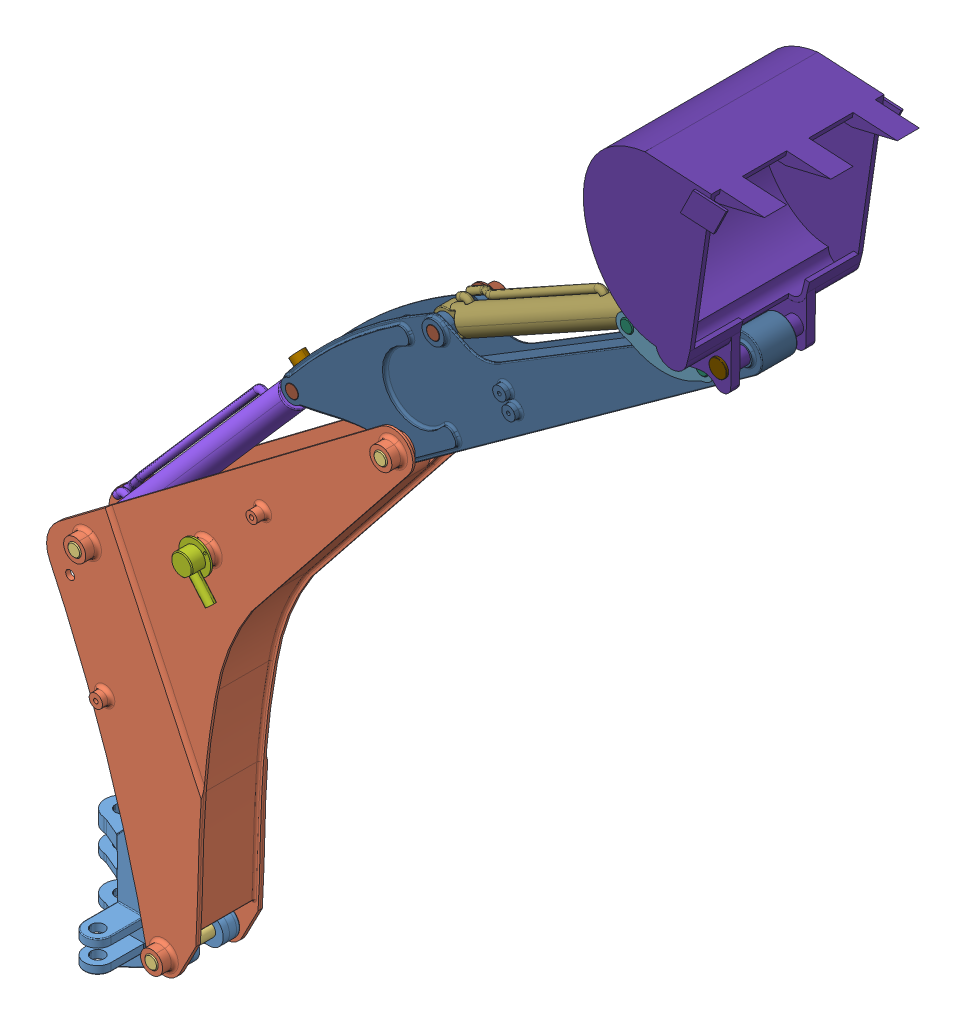
SolidWorks assembly full_assembly, configuration Default. Lengths in mm.
Overall size (1952.98 2370.5 400).
24 component instances, 18 part files, 57 mates.
Components (placement in the parent):
- kingpost-1: kingpost [Default] at origin size (240 290 226)
- boom-4: boom [Default] at (-88.6073 555.0305 -13.75) x (-0.907483 0.420088 0) z (0 0 1) size (576.32 1423.86 198.4)
- boom_pins-1: boom_pins [Default] at (85 -164.3168 63.95) x (-0.343419 0.939182 0) z (0 0 1) size (30 30 195)
- boom_cylinder_barrel-1: boom_cylinder_barrel [Default] at (165.9914 623.896 56.5) x (-0.257112 -0.966382 0) z (-0.966382 0.257112 0) size (614 75.5 93)
- boom_cylinder_rod-1: boom_cylinder_rod [Default] at (155.7069 585.2407 56.5) x (-0.257112 -0.966382 0) z (0.966382 -0.257112 0) size (638.1 60 65)
- kingpost_pin-1: kingpost_pin [Default] at (0 0 56) x (0.057056 0.998371 0) z (0 0 1) size (30 30 118)
- lp1_modification01-1: lp1_modification01 [Default] at (178.847 672.2151 151.75) x (0 0 -1) z (0.761257 0.64845 0) size (210.51 115 72)
- stick_cylinder_barrel-2: stick_cylinder_barrel [Default] at (-64.3049 582.9302 56.5) x (0.656822 0.754046 0) z (-0.754046 0.656822 0) size (632 60 78.05)
- stick_cylinder_rod-1: stick_cylinder_rod [Default] at (-41.3161 609.3218 56.5) x (0.656822 0.754046 0) z (-0.754046 0.656822 0) size (625 50 82)
- boom_pins-2: boom_pins [Default] at (-88.6073 555.0305 63.95) x (0.888222 -0.459415 0) z (0 0 1) size (30 30 195)
- stick-2: stick [Default] at (597.2141 1073.9226 92.5) x (0.81072 0.585434 0) z (0 0 -1) size (1228.04 240.95 123)
- lp2_3_modification01-2: lp2_3_modification01 [Default] at (347.8506 1056.0941 -11.5) x (0 0 1) z (-0.925917 0.377726 0) size (151.51 115 72)
- boom_pins-3: boom_pins [Default] at (597.2141 1073.9226 58.75) x (0.816859 0.576837 0) z (0 0 1) size (30 30 195)
- bucket_cylinder_barrel-1: bucket_cylinder_barrel [Default] at (697.1198 1346.6578 56.5) x (0.874861 0.484375 0) z (-0.484375 0.874861 0) size (507.5 60.7 80.5)
- bucket_cylinder_rod-1: bucket_cylinder_rod [Default] at (709.3679 1353.4391 56.5) x (0.874861 0.484375 0) z (-0.484375 0.874861 0) size (509 50 82)
- tipping_link-1: tipping_link [Default] at (1296.2265 1586.306 114.5) x (-0.999926 -0.012132 0) z (0 0 1) size (220 75.01 26)
- tipping_link-2: tipping_link [Default] at (1296.2265 1586.306 -1.5) x (-0.999926 -0.012132 0) z (0 0 1) size (220 75.01 26)
- stick_pin-1: stick_pin [Default] at (1296.2265 1586.306 54.5) x (0.200545 0.979684 0) z (0 0 1) size (30 30 150)
- stick_pin-2: stick_pin [Default] at (1126.239 1584.2436 54.5) x (0.262192 -0.965016 0) z (0 0 1) size (30 30 150)
- bucket_link-1: bucket_link [Default] at (1126.239 1584.2436 56.5) x (0.869988 0.493073 0) z (0 0 1) size (229.5 95.52 95)
- bucket-1: bucket [Default] at (1411.0239 1858.006 56.5) x (-0.144292 -0.989535 0) z (0 0 1) size (496.86 382.33 400)
- bucket_pin-1: bucket_pin [Default] at (1359.868 1632.2626 66.5) size (40 40 195.4)
- bucket_pin-2: bucket_pin [Default] at (1274.137 1668.066 66.5) size (40 40 195.4)
- lp2_3_modification01-3: lp2_3_modification01 [Default] at (666.4997 1329.7047 -11.5) x (0 0 1) z (-0.999798 0.020111 0) size (151.51 115 72)
Mates (geometry in assembly coordinates):
- Coincident6: coincident aligned: plane of kingpost-1 through (0 0 0) normal (0 1 0)
- Coincident7: coincident aligned: plane of kingpost-1 through (0 0 0) normal (1 0 0)
- Coincident9: coincident aligned: plane of kingpost-1 through (0 0 0) normal (0 0 1)
- Concentric4: concentric aligned: cylinder of kingpost-1 through (85 -164.3168 97) axis (0 0 -1) radius 15; cylinder of boom-4 through (85 -164.3168 -33.27) axis (0 0 -1) radius 15
- Width2: width aligned: plane of boom-4 through (-88.6073 555.0305 -8.5) normal (0 0 1); plane of boom-4 through (-88.6073 555.0305 121.5) normal (0 0 -1); plane of kingpost-1 through (0 0 121) normal (0 0 1); plane of kingpost-1 through (0 0 -8) normal (0 0 -1)
- Concentric5: concentric aligned: cylinder of boom-4 through (85 -164.3168 -33.27) axis (0 0 -1) radius 15; cylinder of boom_pins-1 through (85 -164.3168 -33.55) axis (0 0 -1) radius 15
- Coincident10: coincident anti-aligned: circle of boom-4; circle of boom_pins-1
- Concentric6: concentric aligned: cylinder of boom-4 through (178.847 672.2151 -33.27) axis (0 0 -1) radius 15; cylinder of boom_cylinder_barrel-1 through (178.847 672.2151 36.4) axis (0 0 -1) radius 15
- Width3: width anti-aligned: plane of boom-4 through (-88.6073 555.0305 35.5) normal (0 0 1); plane of boom-4 through (-88.6073 555.0305 77.5) normal (0 0 -1); plane of boom_cylinder_barrel-1 through (165.9914 623.896 36.4) normal (0 0 -1); plane of boom_cylinder_barrel-1 through (165.9914 623.896 76.6) normal (0 0 1)
- Concentric7: concentric anti-aligned: cylinder of kingpost-1 through (0 0 97) axis (0 0 -1) radius 15; cylinder of boom_cylinder_rod-1 through (0 0 76.5) axis (0 0 1) radius 15
- Concentric8: concentric aligned: cylinder of boom_cylinder_barrel-1 through (165.9914 623.896 56.5) axis (0.257112 0.966382 0) radius 30; cylinder of boom_cylinder_rod-1 through (163.0989 613.0242 56.5) axis (0.257112 0.966382 0) radius 15
- LimitDistance1: limit distance = 81 mm anti-aligned: plane of boom_cylinder_barrel-1 through (28.6937 107.8482 56.5) normal (-0.257112 -0.966382 0); plane of boom_cylinder_rod-1 through (-2.7137 32.3865 76.5) normal (0.257112 0.966382 0)
- Concentric9: concentric aligned: cylinder of kingpost-1 through (0 0 97) axis (0 0 -1) radius 15; cylinder of kingpost_pin-1 through (0 0 -3) axis (0 0 -1) radius 15
- Coincident11: coincident aligned: plane of kingpost-1 through (0 0 113) normal (0 0 1); circle of kingpost_pin-1
- Concentric10: concentric anti-aligned: cylinder of boom-4 through (178.847 672.2151 -33.27) axis (0 0 -1) radius 15; cylinder of lp1_modification01-1 through (178.847 672.2151 196.275) axis (0 0 1) radius 14.99
- Coincident12: coincident anti-aligned: plane of boom-4 through (-88.6073 555.0305 151.75) normal (0 0 1); plane of lp1_modification01-1 through (178.847 672.2151 151.75) normal (0 0 -1)
- Concentric12: concentric anti-aligned: cylinder of boom-4 through (-88.6073 555.0305 -33.27) axis (0 0 -1) radius 15; cylinder of stick_cylinder_barrel-2 through (-88.6073 555.0305 39) axis (0 0 1) radius 15
- Width5: width anti-aligned: plane of boom-4 through (-88.6073 555.0305 38.5) normal (0 0 1); plane of stick_cylinder_barrel-2 through (-88.6073 555.0305 74.5) normal (0 0 -1); plane of boom-4 through (-82.6787 598.935 39) normal (0 0 -1); plane of stick_cylinder_barrel-2 through (-45.9311 566.9255 74) normal (0 0 1)
- Concentric14: concentric aligned: cylinder of stick_cylinder_barrel-2 through (-64.3049 582.9302 56.5) axis (-0.656822 -0.754046 0) radius 25; cylinder of stick_cylinder_rod-1 through (-59.8713 588.02 56.5) axis (-0.656822 -0.754046 0) radius 15
- Concentric15: concentric aligned: cylinder of boom-4 through (-88.6073 555.0305 -33.27) axis (0 0 -1) radius 15; cylinder of boom_pins-2 through (-88.6073 555.0305 -33.55) axis (0 0 -1) radius 15
- Coincident13: coincident aligned: plane of boom-4 through (-88.6073 555.0305 159.45) normal (0 0 1); circle of boom_pins-2
- Concentric16: concentric anti-aligned: cylinder of boom-4 through (597.2141 1073.9226 -33.27) axis (0 0 -1) radius 15; cylinder of stick-2 through (597.2141 1073.9226 96.5) axis (0 0 1) radius 15
- Width7: width anti-aligned: plane of boom-4 through (-88.6073 555.0305 106.5) normal (0 0 -1); plane of boom-4 through (-88.6073 555.0305 6.5) normal (0 0 1); plane of stick-2 through (597.2141 1073.9226 106.5) normal (0 0 1); plane of stick-2 through (597.2141 1073.9226 6.5) normal (0 0 -1)
- Concentric17: concentric aligned: cylinder of stick_cylinder_rod-1 through (347.8506 1056.0941 74) axis (0 0 1) radius 15; cylinder of stick-2 through (347.8506 1056.0941 96.5) axis (0 0 1) radius 15
- LimitDistance2: limit distance = 35 mm anti-aligned: plane of stick_cylinder_rod-1 through (342.8485 1023.9813 74) normal (-0.656822 -0.754046 0); plane of stick_cylinder_barrel-2 through (306.7993 1008.9662 56.5) normal (0.656822 0.754046 0)
- Concentric18: concentric anti-aligned: cylinder of stick-2 through (347.8506 1056.0941 96.5) axis (0 0 1) radius 15; cylinder of lp2_3_modification01-2 through (347.8506 1056.0941 -53.075) axis (0 0 -1) radius 14.99
- Coincident15: coincident anti-aligned: plane of stick-2 through (597.2141 1073.9226 -11.5) normal (0 0 -1); plane of lp2_3_modification01-2 through (347.8506 1056.0941 -11.5) normal (0 0 1)
- Concentric19: concentric aligned: cylinder of boom-4 through (597.2141 1073.9226 -33.27) axis (0 0 -1) radius 15; cylinder of boom_pins-3 through (597.2141 1073.9226 -38.75) axis (0 0 -1) radius 15
- Coincident16: coincident aligned: plane of boom-4 through (-88.6073 555.0305 154.25) normal (0 0 1); circle of boom_pins-3
- Concentric20: concentric aligned: cylinder of stick-2 through (666.4997 1329.7047 96.5) axis (0 0 1) radius 15; cylinder of bucket_cylinder_barrel-1 through (666.4997 1329.7047 74.25) axis (0 0 1) radius 15
- Width8: width anti-aligned: plane of stick-2 through (597.2141 1073.9226 38.5) normal (0 0 1); plane of stick-2 through (597.2141 1073.9226 74.5) normal (0 0 -1); plane of bucket_cylinder_barrel-1 through (697.1198 1346.6578 38.75) normal (0 0 -1); plane of bucket_cylinder_barrel-1 through (697.1198 1346.6578 74.25) normal (0 0 1)
- Concentric21: concentric aligned: cylinder of bucket_cylinder_barrel-1 through (697.1198 1346.6578 56.5) axis (-0.874861 -0.484375 0) radius 25; cylinder of bucket_cylinder_rod-1 through (689.6835 1342.5407 56.5) axis (-0.874861 -0.484375 0) radius 15
- LimitDistance3: limit distance = 24 mm anti-aligned: plane of bucket_cylinder_barrel-1 through (1082.0585 1559.7827 56.5) normal (0.874861 0.484375 0); plane of bucket_cylinder_rod-1 through (1112.1686 1554.9473 74.25) normal (-0.874861 -0.484375 0)
- Concentric22: concentric aligned: cylinder of stick-2 through (1296.2265 1586.306 16.5) axis (0 0 -1) radius 15; cylinder of tipping_link-1 through (1296.2265 1586.306 101.5) axis (0 0 -1) radius 15
- Coincident17: coincident anti-aligned: plane of stick-2 through (597.2141 1073.9226 101.5) normal (0 0 1); plane of tipping_link-1 through (1296.2265 1586.306 101.5) normal (0 0 -1)
- Concentric23: concentric aligned: cylinder of stick-2 through (1296.2265 1586.306 16.5) axis (0 0 -1) radius 15; cylinder of tipping_link-2 through (1296.2265 1586.306 -14.5) axis (0 0 -1) radius 15
- Coincident19: coincident anti-aligned: plane of stick-2 through (597.2141 1073.9226 11.5) normal (0 0 -1); plane of tipping_link-2 through (1296.2265 1586.306 11.5) normal (0 0 1)
- Concentric26: concentric anti-aligned: cylinder of bucket_cylinder_rod-1 through (1126.239 1584.2436 74.25) axis (0 0 1) radius 15; cylinder of tipping_link-1 through (1126.239 1584.2436 101.5) axis (0 0 -1) radius 15
- Concentric27: concentric anti-aligned: cylinder of bucket_cylinder_rod-1 through (1126.239 1584.2436 74.25) axis (0 0 1) radius 15; cylinder of tipping_link-2 through (1126.239 1584.2436 -14.5) axis (0 0 -1) radius 15
- Width10: width anti-aligned: plane of tipping_link-2 through (1296.2265 1586.306 11.5) normal (0 0 1); plane of tipping_link-1 through (1296.2265 1586.306 101.5) normal (0 0 -1); plane of bucket_cylinder_rod-1 through (709.3679 1353.4391 38.75) normal (0 0 -1); plane of bucket_cylinder_rod-1 through (709.3679 1353.4391 74.25) normal (0 0 1)
- Concentric29: concentric aligned: cylinder of stick-2 through (1296.2265 1586.306 16.5) axis (0 0 -1) radius 15; cylinder of stick_pin-1 through (1296.2265 1586.306 -20.5) axis (0 0 -1) radius 15
- Concentric30: concentric anti-aligned: cylinder of bucket_cylinder_rod-1 through (1126.239 1584.2436 74.25) axis (0 0 1) radius 15; cylinder of stick_pin-2 through (1126.239 1584.2436 -20.5) axis (0 0 -1) radius 15
- Concentric31: concentric anti-aligned: cylinder of bucket_cylinder_rod-1 through (1126.239 1584.2436 74.25) axis (0 0 1) radius 15; cylinder of bucket_link-1 through (1126.239 1584.2436 9) axis (0 0 -1) radius 15
- Width11: width anti-aligned: plane of bucket_link-1 through (1168.3054 1571.8777 38.5) normal (0 0 1); plane of bucket_cylinder_rod-1 through (1114.3661 1541.3072 74.5) normal (0 0 -1); plane of bucket_link-1 through (709.3679 1353.4391 38.75) normal (0 0 -1); plane of bucket_cylinder_rod-1 through (709.3679 1353.4391 74.25) normal (0 0 1)
- Coincident21: coincident aligned: plane of tipping_link-1 through (1296.2265 1586.306 127.5) normal (0 0 1); circle of stick_pin-1
- Coincident22: coincident aligned: plane of tipping_link-1 through (1296.2265 1586.306 127.5) normal (0 0 1); circle of stick_pin-2
- Concentric33: concentric anti-aligned: cylinder of stick-2 through (1359.868 1632.2626 16.5) axis (0 0 -1) radius 12.5; cylinder of Excavator_bucket1.1-1 through (1359.868 1632.2626 -143.5) axis (0 0 1) radius 12.5
- Concentric34: concentric anti-aligned: cylinder of bucket_link-1 through (1274.137 1668.066 9) axis (0 0 -1) radius 12.5; cylinder of Excavator_bucket1.1-1 through (1274.137 1668.066 -143.5) axis (0 0 1) radius 12.5
- Width12: width anti-aligned: plane of Excavator_bucket1.1-1 through (1359.868 1632.2626 11.5) normal (0 0 1); plane of stick-2 through (1359.868 1632.2626 101.5) normal (0 0 -1); plane of Excavator_bucket1.1-1 through (597.2141 1073.9226 11.5) normal (0 0 -1); plane of stick-2 through (597.2141 1073.9226 101.5) normal (0 0 1)
- Coincident23: coincident anti-aligned: plane of bucket_link-1 through (1314.8987 1652.9319 101.5) normal (0 0 1); circle of Excavator_bucket1.1-1
- Coincident24: coincident aligned: plane of bucket_link-1 through (1266.1794 1625.3198 11.5) normal (0 0 -1); circle of Excavator_bucket1.1-1
- Concentric35: concentric aligned: cylinder of Excavator_bucket1.1-1 through (1359.868 1632.2626 -143.5) axis (0 0 1) radius 12.5; cylinder of bucket_pin-1 through (1359.868 1632.2626 166.27) axis (0 0 1) radius 12.5
- Concentric36: concentric aligned: cylinder of Excavator_bucket1.1-1 through (1274.137 1668.066 -143.5) axis (0 0 1) radius 12.5; cylinder of bucket_pin-2 through (1274.137 1668.066 166.27) axis (0 0 1) radius 12.5
- Coincident26: coincident anti-aligned: plane of Excavator_bucket1.1-1 through (1331.5445 1855.266 151.5) normal (0 0 1); plane of bucket_pin-1 through (1359.868 1632.2626 151.5) normal (0 0 -1)
- Coincident27: coincident anti-aligned: plane of Excavator_bucket1.1-1 through (1331.5445 1855.266 151.5) normal (0 0 1); plane of bucket_pin-2 through (1274.137 1668.066 151.5) normal (0 0 -1)
- Concentric37: concentric anti-aligned: cylinder of stick-2 through (666.4997 1329.7047 96.5) axis (0 0 1) radius 15; cylinder of lp2_3_modification01-3 through (666.4997 1329.7047 -53.075) axis (0 0 -1) radius 14.99
- Coincident28: coincident anti-aligned: plane of stick-2 through (597.2141 1073.9226 -11.5) normal (0 0 -1); plane of lp2_3_modification01-3 through (666.4997 1329.7047 -11.5) normal (0 0 1)
